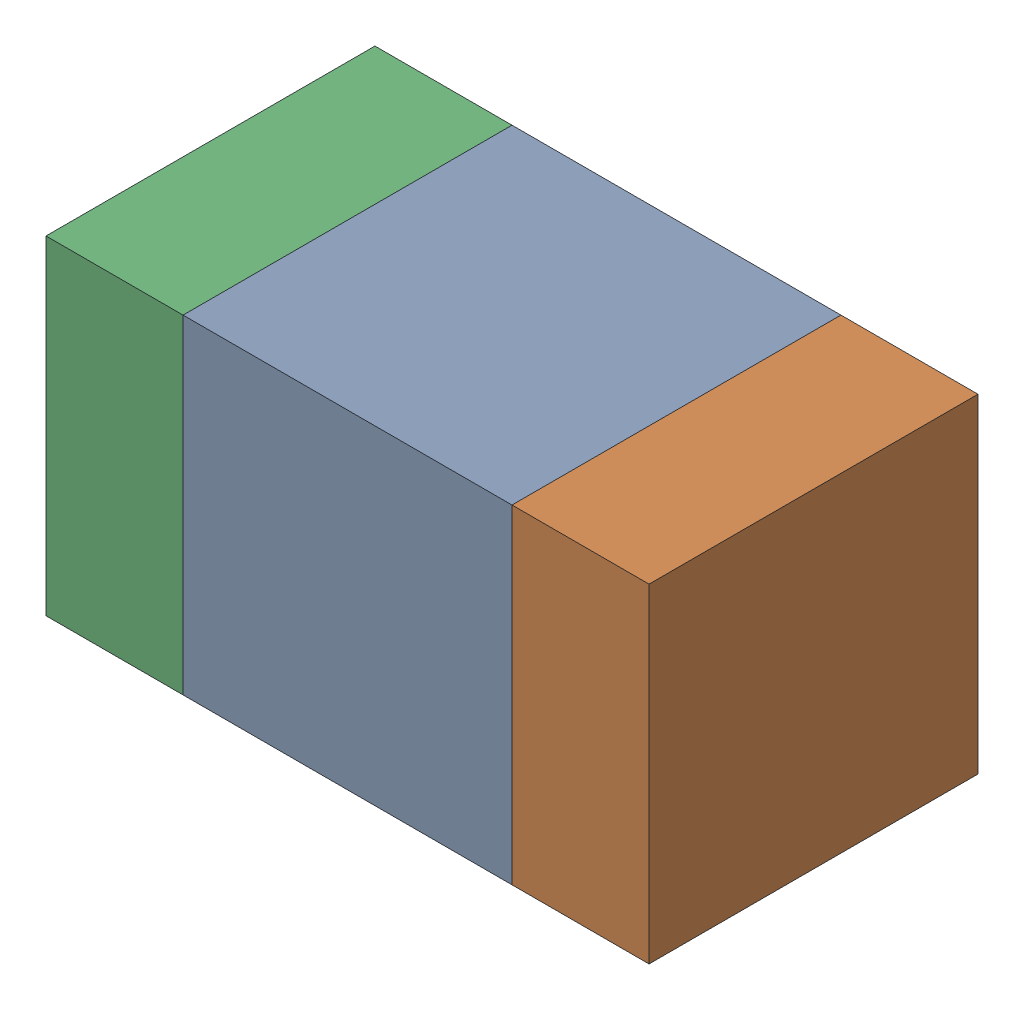
SolidWorks assembly C305_2PCB, configuration Default. Lengths in mm.
Overall size (1.1 0.6 0.6).
6 component instances, 2 part files, 0 mates.
Components (placement in the parent):
- 761606048-1: 761606048 [Default] at (139.1 91.5 0) size (0.6 0.6 0.6)
  - Extruded_9-1: Extruded_9 [Default] at origin size (0.6 0.6 0.6)
- 854785160-1: 854785160 [Default] at (139.525 91.5 0) size (0.25 0.6 0.6)
  - Extruded_19-1: Extruded_19 [Default] at origin size (0.25 0.6 0.6)
- 854785160-2: 854785160 [Default] at (138.675 91.5 0) size (0.25 0.6 0.6)
  - Extruded_19-1: Extruded_19 [Default] at origin size (0.25 0.6 0.6)
